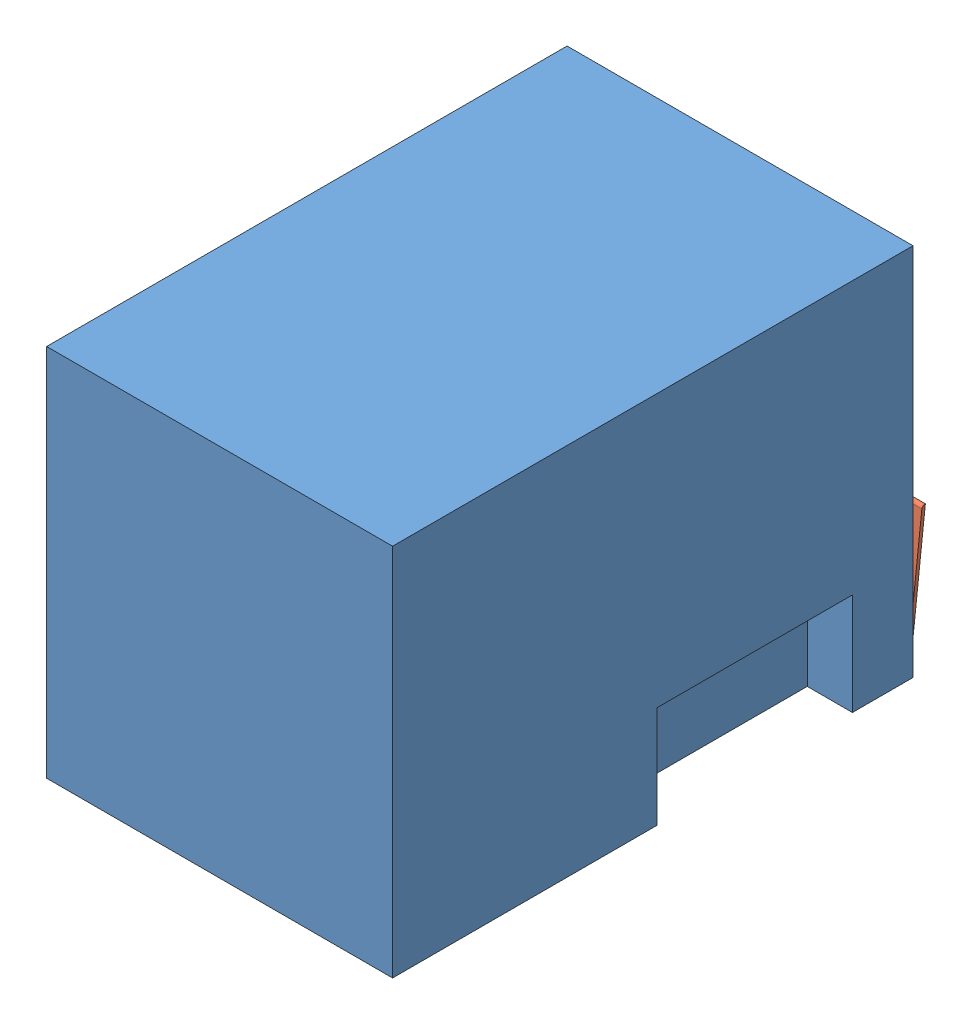
SolidWorks assembly Box with lower doors, configuration Default. Lengths in mm.
Overall size (217.5 235.1 397.24).
3 component instances, 3 part files, 4 mates.
Components (placement in the parent):
- Backside trunk-1: Backside trunk [Default] at (-134.8409 -112.0335 173.62) size (217.5 235.1 327.2)
- Lower_back_door-1: Lower_back_door [Default] at (-134.8409 -112.021 -153.3566) x (-1 0 0) z (0 -0.111707 -0.993741) size (213.5 87.28 2)
- Top_back_door-1: Top_back_door [Default] at (0.9182 0.8181 -407.4662) x (1 0 0) z (0 0.78314 -0.621846) size (213.5 91 113.07)
Mates (geometry in assembly coordinates):
- Coincident4: coincident aligned: line of Backside trunk-1 through (80.6591 -110.0335 -153.58) axis (-1 0 0); line of Lower_back_door^Box with lower doors-1 through (80.6591 -110.0335 -153.58) axis (-1 0 0)
- Coincident5: coincident: point of Backside trunk-1; point of Lower_back_door^Box with lower doors-1
- Coincident6: coincident anti-aligned: line of Backside trunk-1 through (80.6591 121.0665 -153.58) axis (-1 0 0); line of Top_back_door^Box with lower doors-1 through (-132.8409 121.0665 -153.58) axis (1 0 0)
- Coincident7: coincident: point of Backside trunk-1; point of Top_back_door^Box with lower doors-1
